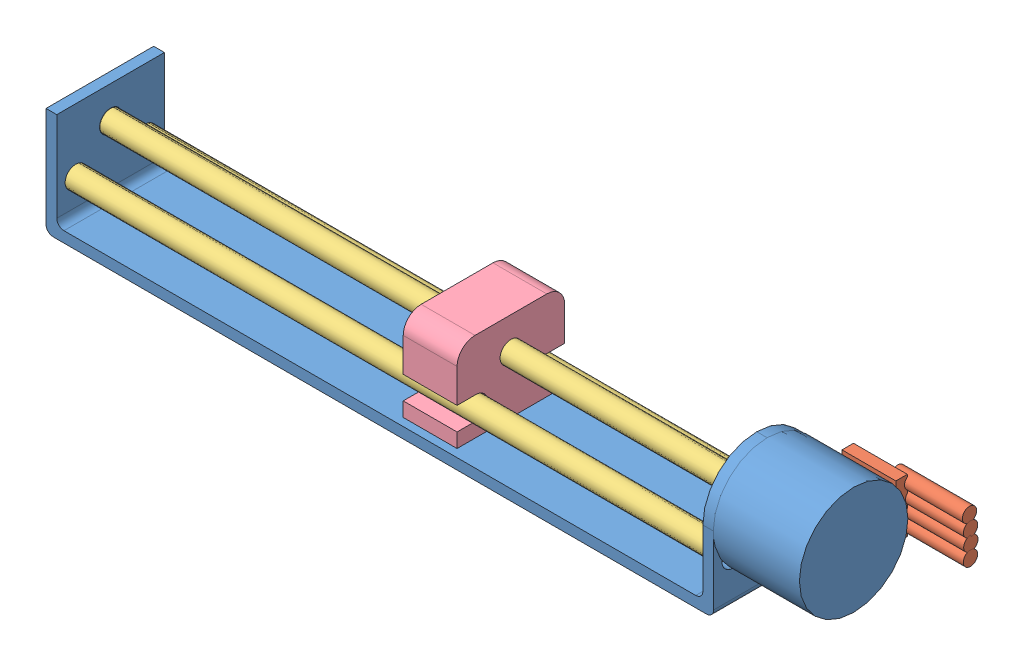
SolidWorks assembly 0204 18_degree_Stepper_motor_ASM, configuration Domyślna. Lengths in mm.
Overall size (123.94 152.42 25.76).
6 component instances, 4 part files, 13 mates.
Components (placement in the parent):
- Podstawa-1: Podstawa [Domyślna] at (-23.4331 3.418 97.5) size (123.94 152.42 15.11)
- PCB_złożenie_PART_ASM-1: PCB_złożenie_PART_ASM [Domyślna] at (30.2257 4.23 104.2) x (1 0 0) z (0 0 -1) size (19.02 7.5 10.76)
- prowadnica-1: prowadnica [Domyślna] at (21.2899 4.3448 105) x (0 0 1) z (-1 0 0) size (3 3 90)
- suwak-1: suwak [Domyślna] at (-12.9526 -22.7417 105.613) x (0 -1 0) z (-1 0 0) size (12.4 15 7.5)
- prowadnica-2: prowadnica [Domyślna] at (-68.7101 0.0448 109.845) x (0 0 -1) z (1 0 0) size (3 3 90)
- prowadnica-3: prowadnica [Domyślna] at (21.2899 0.0448 100.155) x (0 0 1) z (-1 0 0) size (3 3 90)
Mates (geometry in assembly coordinates):
- Równolegle1: parallel anti-aligned: plane of Podstawa-1 through (-69.2101 -5.1552 97.5) normal (0 0 -1); plane of PCB_złożenie_PART_ASM-1 through (29.4171 4.3448 97.5) normal (0 0 1)
- Równolegle2: parallel anti-aligned: plane of Podstawa-1 through (-67.7101 -4.6552 112.5) normal (0 1 0); plane of PCB_złożenie_PART_ASM-1 through (25.6671 0.5948 95.9) normal (0 -1 0)
- Wspólnie1: coincident anti-aligned: plane of Podstawa-1 through (-69.2101 -5.1552 97.5) normal (0 0 -1); plane of PCB_złożenie_PART_ASM-1 through (29.4171 4.3448 97.5) normal (0 0 1)
- Wspólnie2: coincident aligned: plane of Podstawa-1 through (-23.4331 4.3448 97.5) normal (0 -1 0); plane of PCB_złożenie_PART_ASM-1 through (30.2257 4.3448 104.2) normal (0 -1 0)
- Wspólnie3: coincident anti-aligned: plane of Podstawa-1 through (21.2899 -3.6552 112.5) normal (-1 0 0); plane of prowadnica-1 through (21.2899 4.3448 105) normal (1 0 0)
- Koncentryczne1: concentric anti-aligned: circle of Podstawa-1; circle of prowadnica-1
- Wspólnie4: coincident aligned: plane of Podstawa-1 through (-68.7101 8.8448 112.5) normal (0 1 0); plane of suwak-1 through (-20.4526 8.8448 112.5) normal (0 1 0)
- Równolegle3: parallel anti-aligned: plane of Podstawa-1 through (-68.7101 8.8448 112.5) normal (1 0 0); plane of suwak-1 through (-20.4526 -22.7417 105.613) normal (-1 0 0)
- Wspólnie6: coincident: line of Podstawa-1 through (20.2899 -4.6552 112.5) axis (-1 0 0); plane of suwak-1 through (-20.4526 8.8448 112.5) normal (0 0 1)
- Wspólnie7: coincident anti-aligned: circle of Podstawa-1; cylinder of prowadnica-2 through (21.2899 0.0448 109.845) axis (-1 0 0) radius 1.5
- Wspólnie9: coincident anti-aligned: plane of Podstawa-1 through (21.2899 -3.6552 112.5) normal (-1 0 0); plane of prowadnica-2 through (21.2899 0.0448 109.845) normal (1 0 0)
- Wspólnie10: coincident anti-aligned: circle of Podstawa-1; cylinder of prowadnica-3 through (-68.7101 0.0448 100.155) axis (1 0 0) radius 1.5
- Wspólnie11: coincident anti-aligned: plane of Podstawa-1 through (21.2899 -3.6552 112.5) normal (-1 0 0); plane of prowadnica-3 through (21.2899 0.0448 100.155) normal (1 0 0)
